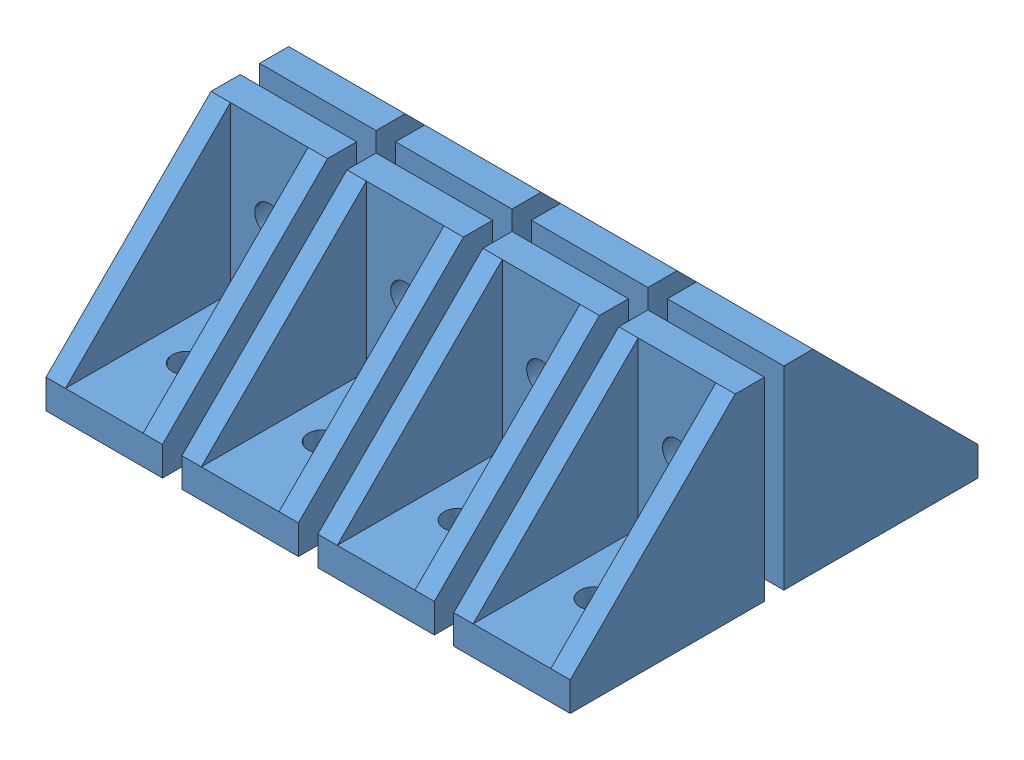
SolidWorks assembly Baugruppe1, configuration Standard. Lengths in mm.
Overall size (54 20 42).
8 component instances, 1 part files, 0 mates.
Components (placement in the parent):
- Winkel-1: Winkel [Standard] at (-7.2441 -6.1752 20) size (12 20 20)
- Winkel-2: Winkel [Standard] at (6.7559 -6.1752 20) size (12 20 20)
- Winkel-3: Winkel [Standard] at (20.7559 -6.1752 20) size (12 20 20)
- Winkel-4: Winkel [Standard] at (34.7559 -6.1752 20) size (12 20 20)
- Winkel-5: Winkel [Standard] at (6.7559 -6.1752 18) x (-1 0 0) z (0 0 -1) size (12 20 20)
- Winkel-6: Winkel [Standard] at (-7.2441 -6.1752 18) x (-1 0 0) z (0 0 -1) size (12 20 20)
- Winkel-7: Winkel [Standard] at (20.7559 -6.1752 18) x (-1 0 0) z (0 0 -1) size (12 20 20)
- Winkel-8: Winkel [Standard] at (34.7559 -6.1752 18) x (-1 0 0) z (0 0 -1) size (12 20 20)
